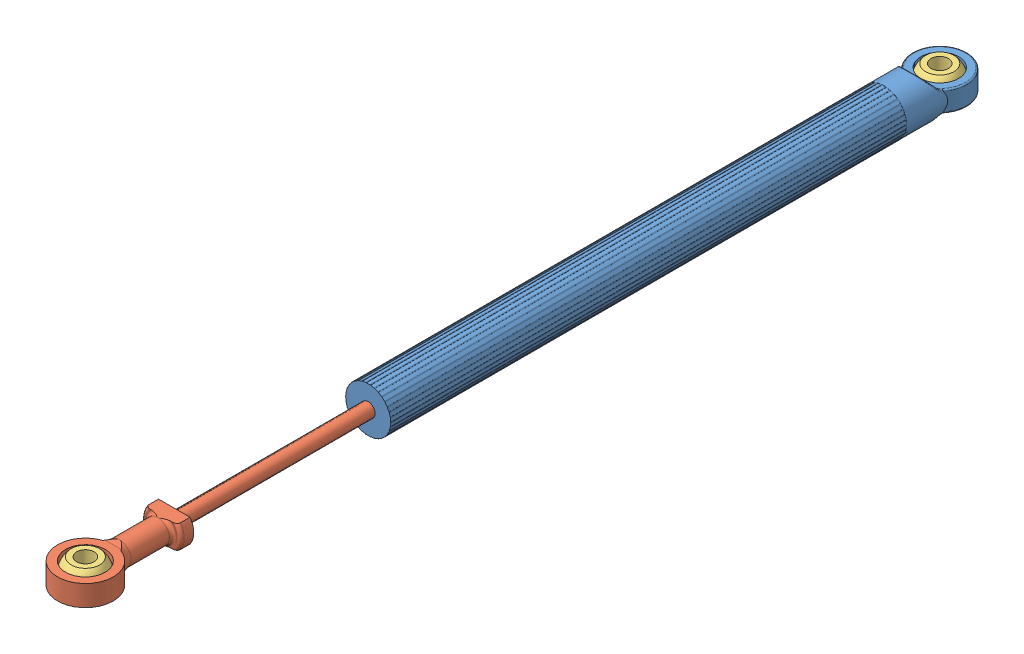
SolidWorks assembly Linear Potentiometer, configuration Default. Lengths in mm.
4 component instances, 3 part files, 13 mates.
Components (placement in the parent):
- Penny Giles Potentiometer Body-1: Penny Giles Potentiometer Body [Default] at (0 0 164) x (0 -1 0) z (0 0 -1) size (13.67 15.51 171.75)
- Potentiometer Top-1: Potentiometer Top [Default] at (0 0 63.46) x (0 -1 0) z (0 0 1) size (9.08 16 189.67)
- M5 Spherical-1: M5 Spherical [Default] at (0 0 245.13) x (1 0 0) z (0 -1 0) size (11.4 11.4 8)
- M5 Spherical-2: M5 Spherical [Default] x (0.127841 0 -0.991795) z (0 1 0) size (11.4 11.4 8)
Mates (geometry in assembly coordinates):
- Coincident1: coincident: line of Penny Giles Potentiometer Body-1 through (0 0 -30.9327) axis (0 0 1); point of M5 Spherical-2
- Coincident2: coincident: line of Potentiometer Top-1 through (0 0 -17.44) axis (0 0 1); point of M5 Spherical-1
- Coincident6: coincident: point of M5 Spherical-2; point of assembly
- Concentric3: concentric anti-aligned: cylinder of Penny Giles Potentiometer Body-1 through (0 0 14) axis (0 0 1) radius 2; cylinder of Potentiometer Top-1 through (0 0 219.63) axis (0 0 -1) radius 2
- LimitDistance1: limit distance = 55.63 mm anti-aligned: plane of Potentiometer Top-1 through (0 0 219.63) normal (0 0 -1); plane of Penny Giles Potentiometer Body-1 through (0 0 164) normal (0 0 1)
- Coincident14: coincident aligned: plane of Penny Giles Potentiometer Body-1; plane of Potentiometer Top-1
- Coincident15: coincident anti-aligned: plane of Penny Giles Potentiometer Body-1; plane of assembly through (0 0 0) normal (0 1 0)
- Coincident16: coincident aligned: plane of M5 Spherical-2 through (0 0 0) normal (0 1 0); plane of assembly through (0 0 0) normal (0 1 0)
- Coincident17: coincident anti-aligned: plane of M5 Spherical-1 through (0 0 245.13) normal (0 -1 0); plane of assembly through (0 0 0) normal (0 1 0)
- Concentric4: concentric: cylinder of Penny Giles Potentiometer Body-1 through (0 3 0) axis (0 -1 0) radius 5.4544; sphere of M5 Spherical-2
- Concentric5: concentric: cylinder of Potentiometer Top-1 through (0 5 245.13) axis (0 -1 0) radius 5.7; sphere of M5 Spherical-1
- Coincident20: coincident: point of M5 Spherical-2; point of assembly
- Coincident21: coincident anti-aligned: plane of Penny Giles Potentiometer Body-1; plane of assembly through (0 0 0) normal (1 0 0)
